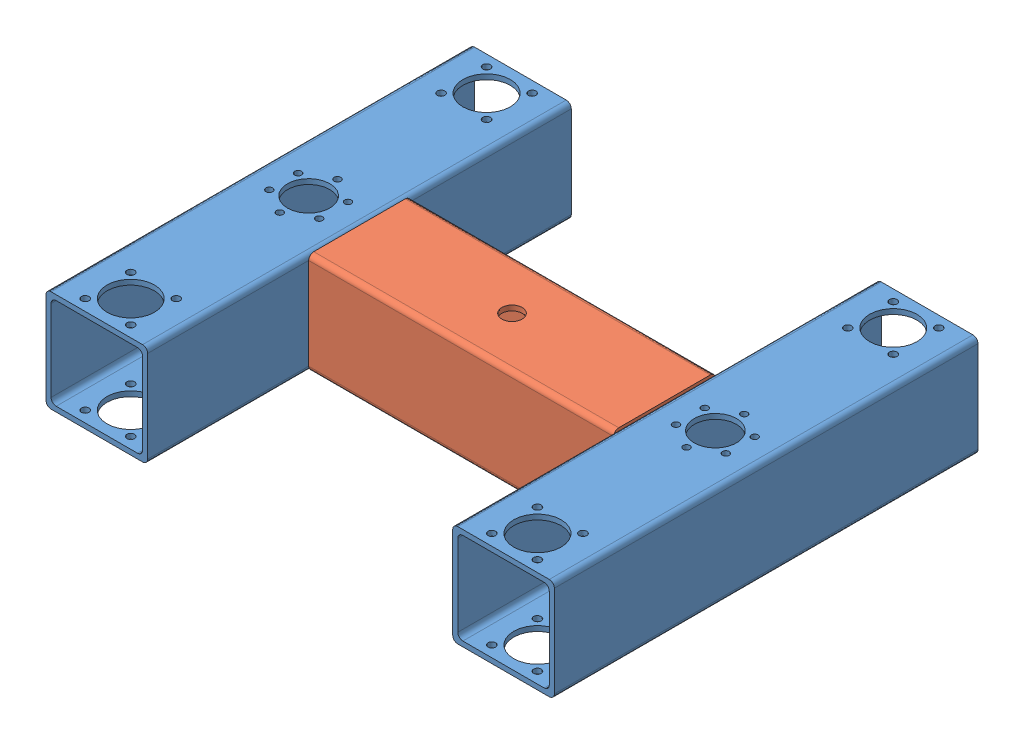
SolidWorks assembly moving_frame_solo, configuration Domyślna. Lengths in mm.
Overall size (300 60 250).
3 component instances, 2 part files, 24 mates.
Components (placement in the parent):
- profile_60x60x3-1: profile_60x60x3 [Domyślna] at (1.1192 25.5119 92.8006) size (60 60 250)
- profile_60x60x3-2: profile_60x60x3 [Domyślna] at (241.1192 25.5119 92.8006) size (60 60 250)
- profile_60x60x3_1-1: profile_60x60x3_1 [Domyślna] at (211.1192 25.5119 217.8006) x (0 0 1) z (-1 0 0) size (60 60 180)
Mates (geometry in assembly coordinates):
- Coincident1: coincident aligned: plane of profile_60x60x3-1 through (1.1192 25.5119 342.8006) normal (0 0 1); plane of profile_60x60x3-2 through (241.1192 25.5119 342.8006) normal (0 0 1)
- Coincident2: coincident aligned: plane of profile_60x60x3-1 through (-28.8808 55.5119 342.8006) normal (0 1 0); plane of profile_60x60x3-2 through (211.1192 55.5119 342.8006) normal (0 1 0)
- Coincident3: coincident anti-aligned: plane of profile_60x60x3-1 through (31.1192 55.5119 342.8006) normal (1 0 0); plane of profile_60x60x3_1-1 through (31.1192 25.5119 217.8006) normal (-1 0 0)
- Coincident4: coincident aligned: plane of profile_60x60x3-1 through (-28.8808 55.5119 342.8006) normal (0 1 0); plane of profile_60x60x3_1-1 through (31.1192 55.5119 187.8006) normal (0 1 0)
- Coincident5: coincident anti-aligned: plane of profile_60x60x3-2 through (211.1192 55.5119 342.8006) normal (-1 0 0); plane of profile_60x60x3_1-1 through (211.1192 25.5119 217.8006) normal (1 0 0)
- Distance1: distance = 95 mm aligned: plane of profile_60x60x3_1-1 through (31.1192 55.5119 247.8006) normal (0 0 1); plane of profile_60x60x3-2 through (241.1192 25.5119 342.8006) normal (0 0 1)
- Concentric1: concentric anti-aligned: cylinder of profile_60x60x3-1 through (-13.6032 55.5119 209.3006) axis (0 -1 0) radius 2; cylinder of tr10x2.step-2 through (-13.6032 48.4409 209.3006) axis (0 1 0) radius 2.5
- Concentric2: concentric anti-aligned: cylinder of profile_60x60x3-1 through (1.1192 55.5119 200.8006) axis (0 -1 0) radius 2; cylinder of tr10x2.step-2 through (1.1192 48.4409 200.8006) axis (0 1 0) radius 2.5
- Coincident7: coincident anti-aligned: plane of profile_60x60x3-1 through (-28.8808 55.5119 342.8006) normal (0 1 0); plane of tr10x2.step-2 through (1.1192 55.5119 217.8006) normal (0 -1 0)
- Concentric3: concentric anti-aligned: cylinder of profile_60x60x3-2 through (255.8416 55.5119 209.3006) axis (0 -1 0) radius 2; cylinder of tr10x2.step-3 through (255.8416 48.4409 209.3006) axis (0 1 0) radius 2.5
- Concentric4: concentric anti-aligned: cylinder of profile_60x60x3-2 through (241.1192 55.5119 200.8006) axis (0 -1 0) radius 2; cylinder of tr10x2.step-3 through (241.1192 48.4409 200.8006) axis (0 1 0) radius 2.5
- Coincident8: coincident anti-aligned: plane of profile_60x60x3-2 through (211.1192 55.5119 342.8006) normal (0 1 0); plane of tr10x2.step-3 through (241.1192 55.5119 217.8006) normal (0 -1 0)
- Coincident9: coincident anti-aligned: cylinder of profile_60x60x3-2 through (227.6842 55.5119 336.2356) axis (0 -1 0) radius 2.25; circle of LMK16UU-1
- Concentric5: concentric anti-aligned: cylinder of profile_60x60x3-2 through (254.5542 55.5119 309.3656) axis (0 -1 0) radius 2.25; cylinder of LMK16UU-1 through (254.5542 49.148 309.3656) axis (0 1 0) radius 2.25
- Coincident11: coincident anti-aligned: plane of profile_60x60x3-1 through (-28.8808 55.5119 342.8006) normal (0 1 0); plane of LMK16UU-1 through (241.1192 55.5119 322.8006) normal (0 -1 0)
- Concentric6: concentric anti-aligned: cylinder of profile_60x60x3-2 through (254.5542 55.5119 126.2356) axis (0 -1 0) radius 2.25; cylinder of LMK16UU-2 through (254.5542 57.4119 126.2356) axis (0 1 0) radius 3.75
- Concentric7: concentric anti-aligned: cylinder of profile_60x60x3-2 through (227.6842 55.5119 99.3656) axis (0 -1 0) radius 2.25; cylinder of LMK16UU-2 through (227.6842 57.4119 99.3656) axis (0 1 0) radius 3.75
- Coincident12: coincident anti-aligned: plane of profile_60x60x3-2 through (211.1192 55.5119 342.8006) normal (0 1 0); plane of LMK16UU-2 through (241.1192 55.5119 112.8006) normal (0 -1 0)
- Concentric8: concentric anti-aligned: cylinder of profile_60x60x3-1 through (14.5542 55.5119 126.2356) axis (0 -1 0) radius 2.25; cylinder of LMK16UU-3 through (14.5542 57.4119 126.2356) axis (0 1 0) radius 3.75
- Concentric9: concentric anti-aligned: cylinder of profile_60x60x3-1 through (-12.3158 55.5119 99.3656) axis (0 -1 0) radius 2.25; cylinder of LMK16UU-3 through (-12.3158 57.4119 99.3656) axis (0 1 0) radius 3.75
- Coincident13: coincident anti-aligned: plane of profile_60x60x3-1 through (-28.8808 55.5119 342.8006) normal (0 1 0); plane of LMK16UU-3 through (1.1192 55.5119 112.8006) normal (0 -1 0)
- Concentric10: concentric anti-aligned: cylinder of profile_60x60x3-1 through (14.5542 55.5119 336.2356) axis (0 -1 0) radius 2.25; cylinder of LMK16UU-4 through (14.5542 49.148 336.2356) axis (0 1 0) radius 2.25
- Concentric11: concentric anti-aligned: cylinder of profile_60x60x3-1 through (-12.3158 55.5119 309.3656) axis (0 -1 0) radius 2.25; cylinder of LMK16UU-4 through (-12.3158 49.148 309.3656) axis (0 1 0) radius 2.25
- Coincident14: coincident anti-aligned: plane of profile_60x60x3-1 through (-28.8808 55.5119 342.8006) normal (0 1 0); plane of LMK16UU-4 through (1.1192 55.5119 322.8006) normal (0 -1 0)
